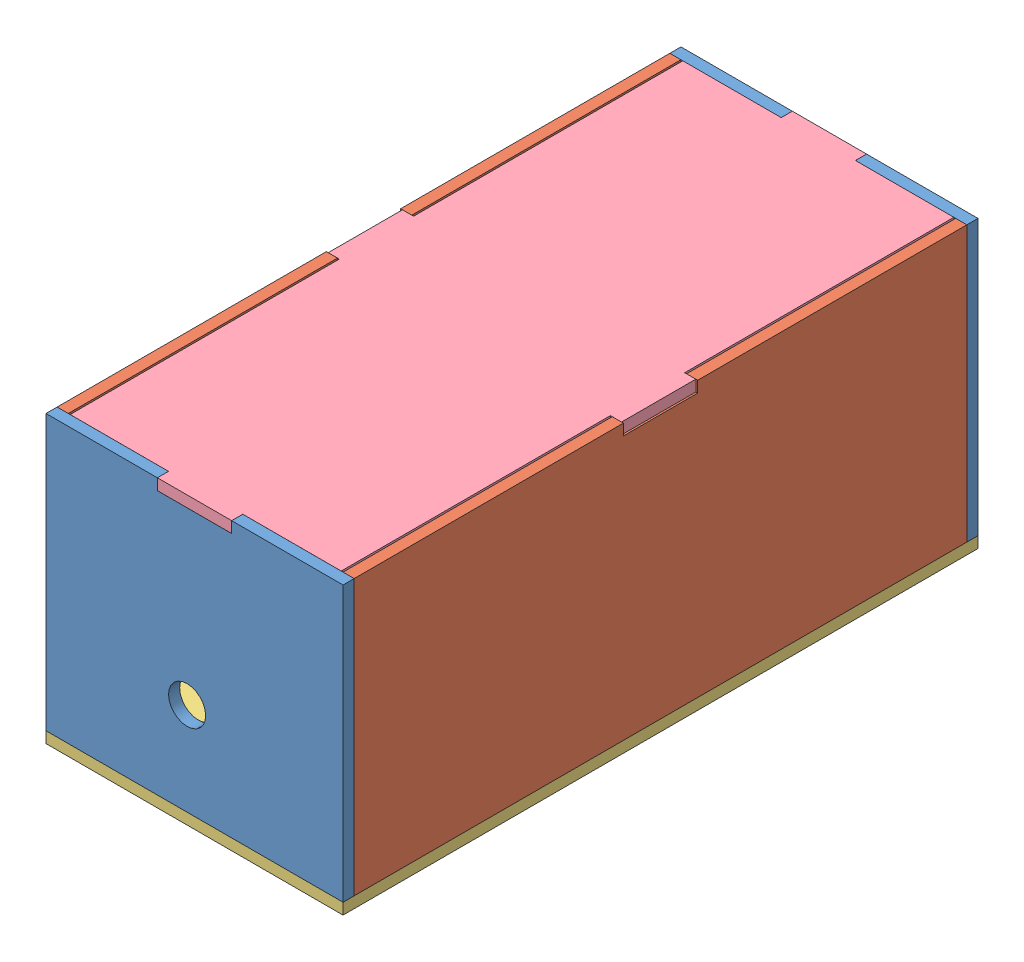
SolidWorks assembly Mont1, configuration Valor predeterminado. Lengths in mm.
Overall size (80 77.01 171).
6 component instances, 4 part files, 12 mates.
Components (placement in the parent):
- Fundo-Novo-caixa-luz-1: Fundo-Novo-caixa-luz [Valor predeterminado] at (12.2603 -18.6317 80) size (80 74 3)
- Lateral-caixa-luz-nova-1: Lateral-caixa-luz-nova [Valor predeterminado] at (12.2603 12.9942 0.8613) x (0 0 1) z (-1 0 0) size (165 74 3)
- Lateral-caixa-luz-nova-2: Lateral-caixa-luz-nova [Valor predeterminado] at (-64.7397 12.9942 0.8613) x (0 0 1) z (-1 0 0) size (165 74 3)
- Fundo-Novo-caixa-luz-2: Fundo-Novo-caixa-luz [Valor predeterminado] at (12.2603 -18.6317 -88) size (80 74 3)
- Base-Nova-caixa-luz-1: Base-Nova-caixa-luz [Valor predeterminado] at (-31.3676 -44.4787 -61.2558) x (1 0 0) z (0 1 0) size (80 171 3)
- Tampa-Caixa-Luz-1: Tampa-Caixa-Luz [Valor predeterminado] at (-24.7397 29.527 -2.5) x (0 0 -1) z (0 1 0) size (171 79 3)
Mates (geometry in assembly coordinates):
- Coincidente3: coincident anti-aligned: plane of Fundo-Novo-caixa-luz-1 through (12.2603 -18.6317 80) normal (0 0 -1); plane of Lateral-caixa-luz-nova-1 through (15.2603 12.9942 80) normal (0 0 1)
- Coincidente4: coincident aligned: plane of Fundo-Novo-caixa-luz-1 through (15.2603 -18.6317 83) normal (1 0 0); plane of Lateral-caixa-luz-nova-1 through (15.2603 12.9942 0.8613) normal (1 0 0)
- Coincidente5: coincident aligned: plane of Fundo-Novo-caixa-luz-1 through (12.2603 -41.4787 83) normal (0 -1 0); plane of Lateral-caixa-luz-nova-1 through (15.2603 -41.4787 0.8613) normal (0 -1 0)
- Coincidente6: coincident anti-aligned: plane of Lateral-caixa-luz-nova-1 through (15.2603 12.9942 -85) normal (0 0 -1); plane of Fundo-Novo-caixa-luz-2 through (12.2603 -18.6317 -85) normal (0 0 1)
- Coincidente7: coincident aligned: plane of Lateral-caixa-luz-nova-1 through (15.2603 12.9942 0.8613) normal (1 0 0); plane of Fundo-Novo-caixa-luz-2 through (15.2603 -18.6317 -85) normal (1 0 0)
- Coincidente8: coincident aligned: plane of Lateral-caixa-luz-nova-1 through (15.2603 -41.4787 0.8613) normal (0 -1 0); plane of Fundo-Novo-caixa-luz-2 through (12.2603 -41.4787 -85) normal (0 -1 0)
- Coincidente11: coincident anti-aligned: plane of Lateral-caixa-luz-nova-2 through (-61.7397 12.9942 -85) normal (0 0 -1); plane of Fundo-Novo-caixa-luz-2 through (12.2603 -18.6317 -85) normal (0 0 1)
- Coincidente12: coincident aligned: plane of Lateral-caixa-luz-nova-2 through (-64.7397 12.9942 0.8613) normal (-1 0 0); plane of Fundo-Novo-caixa-luz-2 through (-64.7397 -18.6317 -85) normal (-1 0 0)
- Coincidente13: coincident aligned: plane of Lateral-caixa-luz-nova-2 through (-61.7397 -41.4787 0.8613) normal (0 -1 0); plane of Fundo-Novo-caixa-luz-2 through (12.2603 -41.4787 -85) normal (0 -1 0)
- Coincidente17: coincident anti-aligned: plane of Lateral-caixa-luz-nova-2 through (-61.7397 -41.4787 0.8613) normal (0 -1 0); plane of Base-Nova-caixa-luz-1 through (-31.3676 -41.4787 -61.2558) normal (0 1 0)
- Coincidente31: coincident anti-aligned: plane of Fundo-Novo-caixa-luz-2 through (-14.7397 -18.6317 -85) normal (-1 0 0); plane of Tampa-Caixa-Luz-1 through (-14.7397 32.527 -85) normal (1 0 0)
- Coincidente32: coincident aligned: plane of Fundo-Novo-caixa-luz-2 through (12.2603 -18.6317 -88) normal (0 0 -1); plane of Tampa-Caixa-Luz-1 through (-34.7397 32.527 -88) normal (0 0 -1)
